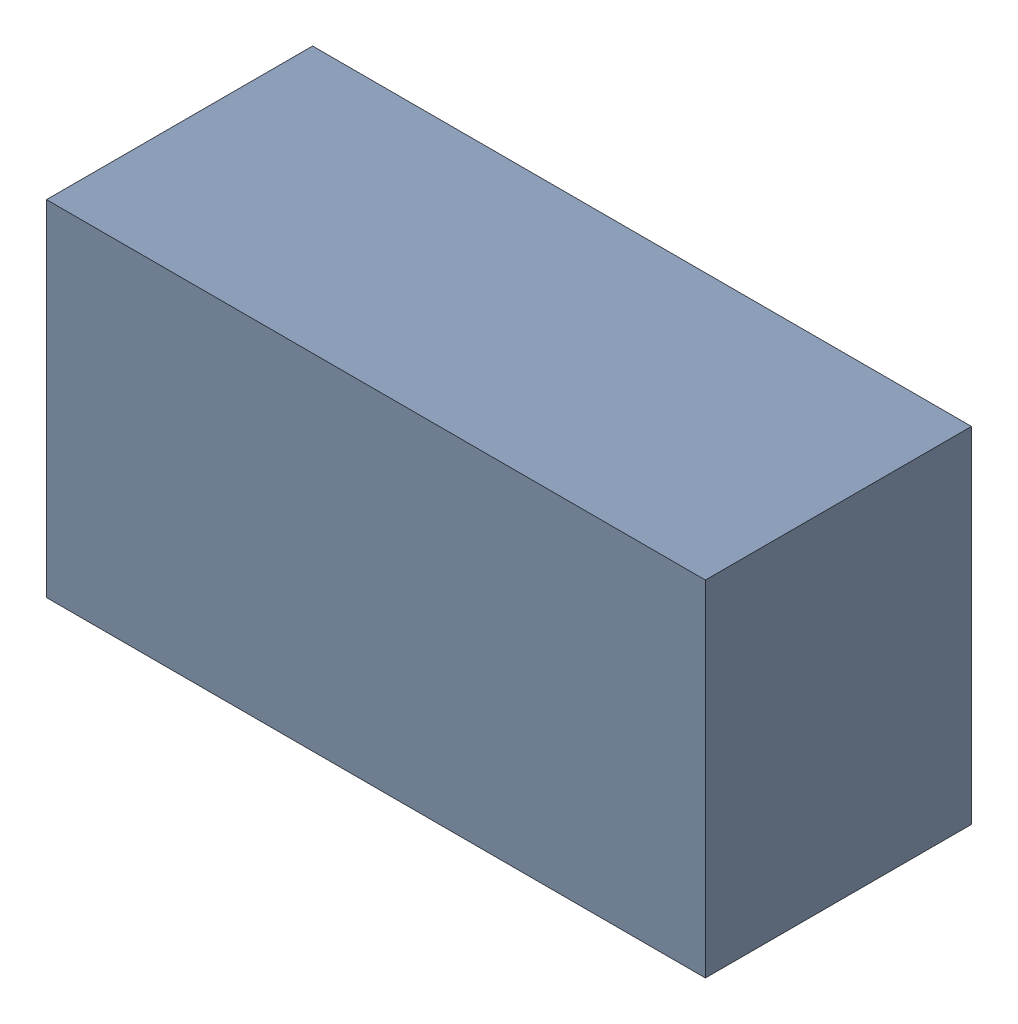
SolidWorks assembly 6327397888, configuration Default. Lengths in mm.
Overall size (0.63 0.33 0.25).
2 component instances, 1 part files, 0 mates.
Components (placement in the parent):
- 6701982208-1:  [Default] at (27.7 14.8 0) (suppressed, hidden)
- Extruded-16-1: Extruded-16 [Default] at origin size (0.63 0.33 0.25)
